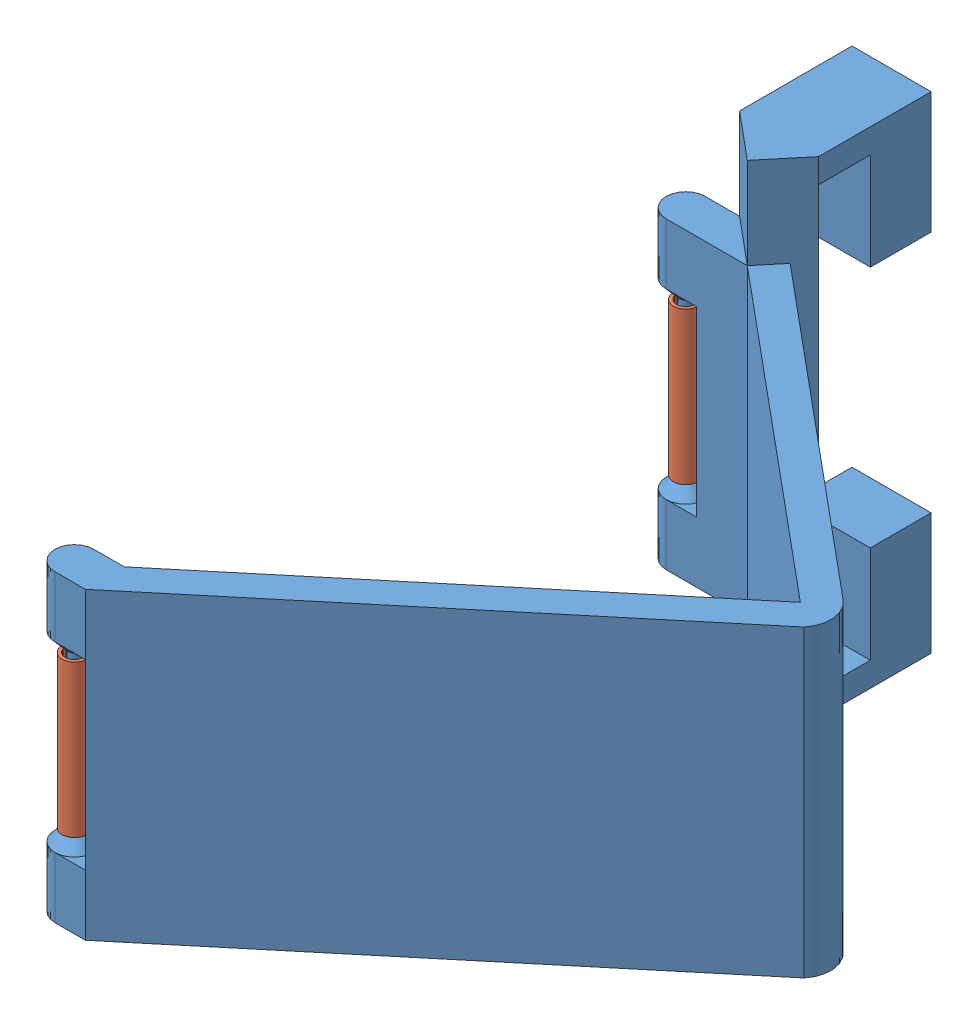
SolidWorks assembly 装配体1, configuration 默认. Lengths in mm.
Overall size (73.86 80 146.29).
3 component instances, 2 part files, 2 mates.
Components (placement in the parent):
- 抓手右-1: 抓手右 [默认] at (-31.6981 -23.2884 162.4841) size (73.86 80 146.29)
- 套筒-1: 套筒 [默认] at (-37.3621 -11.3564 216.2383) size (4 25 4)
- 套筒-2: 套筒 [默认] at (-37.3621 -11.3564 115.685) size (4 25 4)
Mates (geometry in assembly coordinates):
- 重合1: coincident aligned: cone of 抓手右-1 through (-37.3621 -10.7884 216.2383) axis (0 1 0); circle of 套筒-1
- 重合2: coincident aligned: cone of 抓手右-1 through (-37.3621 -10.7884 115.685) axis (0 1 0); circle of 套筒-2
